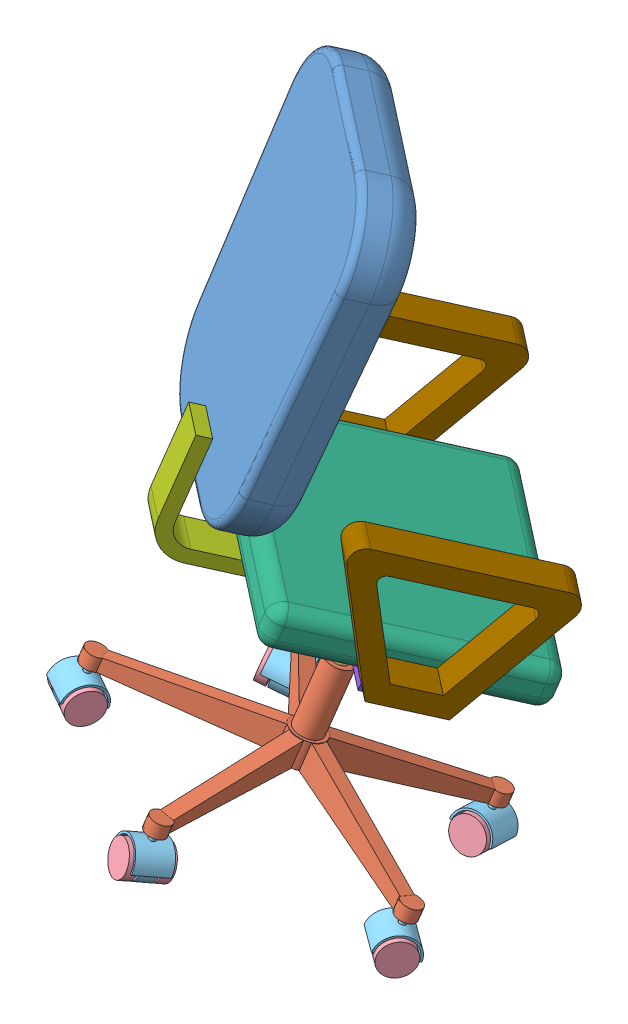
SolidWorks assembly Assem2, configuration Default. Lengths in mm.
Overall size (662.53 1073.07 669.63).
23 component instances, 9 part files, 42 mates.
Components (placement in the parent):
- back rest-1: back rest [Default] at (-3518.8122 357.0651 -759.5656) x (-0.791753 0.043601 -0.609283) z (-0.242596 -0.937857 0.248135) size (389.74 80 499.37)
- base legs-1: base legs [Default] at (-3351.6108 -73.638 -779.0281) x (0.131839 0.221531 0.9662) z (-0.961127 0.26711 0.069903) size (482.25 160 505.53)
- nuematic rod-1: nuematic rod [Default] at (-3337.055 -17.3665 -793.9162) x (-0.791753 0.043601 -0.609283) z (0.560602 -0.344271 -0.753129) size (24 200 24)
- wheel-1: wheel [Default] at (-3597.754 -47.6682 -679.7172) x (0.280239 0.901558 -0.329635) z (-0.375607 0.419001 0.826654) size (50 15 50)
- wheels-1: wheels [Default] at (-3584.5031 -49.286 -672.8764) x (-0.400951 0.329838 0.854661) z (-0.242596 -0.937857 0.248135) size (60 50 75)
- ceat-2: ceat [Default] at (-3273.8894 228.6402 -860.2391) x (-0.791753 0.043601 -0.609283) z (-0.560602 0.344271 0.753129) size (400 60 350)
- wheel-2: wheel [Default] at (-3139.6275 -175.4673 -714.8494) x (0.520852 0.521565 -0.675783) z (-0.265905 0.851384 0.45215) size (50 15 50)
- wheel-3: wheel [Default] at (-3327.5473 -79.4294 -535.5873) x (-0.50983 0.70779 -0.488985) z (-0.773121 -0.62626 -0.100413) size (50 15 50)
- wheel-4: wheel [Default] at (-3546.6433 -130.494 -942.7976) x (0.497624 0.789061 0.360211) z (0.221963 -0.517294 0.826522) size (50 15 50)
- wheel-5: wheel [Default] at (-3338.8664 -69.6238 -509.5925) x (0.849668 -0.250011 0.464284) z (-0.368384 -0.911407 0.183385) size (50 15 50)
- wheel-6: wheel [Default] at (-3571.2521 -50.9037 -666.0356) x (-0.466913 -0.119328 0.876215) z (0.040078 0.98698 0.155769) size (50 15 50)
- wheel-7: wheel [Default] at (-3254.2495 -217.0971 -984.2579) x (0.711 0.648676 -0.271476) z (-0.680602 0.731877 -0.03373) size (50 15 50)
- wheel-8: wheel [Default] at (-3115.2922 -177.1415 -697.3854) x (-0.290606 -0.902298 0.318444) z (-0.507484 0.427485 0.748142) size (50 15 50)
- wheel-9: wheel [Default] at (-3521.4879 -140.4343 -955.7744) x (-0.537997 -0.377647 -0.753619) z (-0.086352 -0.864635 0.494923) size (50 15 50)
- wheel-10: wheel [Default] at (-3248.9453 -210.8346 -955.4022) x (-0.804244 0.593998 0.018921) z (0.56739 0.776911 -0.272908) size (50 15 50)
- wheels-2: wheels [Default] at (-3127.4599 -176.3044 -706.1174) x (0.532108 -0.342504 -0.774307) z (-0.242596 -0.937857 0.248135) size (60 50 75)
- wheels-3: wheels [Default] at (-3251.5974 -213.9659 -969.83) x (0.95388 -0.277214 -0.115178) z (-0.242596 -0.937857 0.248135) size (60 50 75)
- wheels-4: wheels [Default] at (-3333.2069 -74.5266 -522.5899) x (0.89375 -0.116586 0.433149) z (-0.242596 -0.937857 0.248135) size (60 50 75)
- wheels-5: wheels [Default] at (-3534.0656 -135.4642 -949.286) x (0.487898 0.103127 0.866787) z (-0.242596 -0.937857 0.248135) size (60 50 75)
- ceat rest connector-1: ceat rest connector [Default] at (-3382.5087 277.3327 -661.4926) x (-0.560602 0.344271 0.753129) z (-0.242596 -0.937857 0.248135) size (157.54 60 170)
- ceat frame-1: ceat frame [Default] at (-3287.4946 172.7003 -843.1689) x (-0.791753 0.043601 -0.609283) z (-0.560602 0.344271 0.753129) size (430 10 200)
- hand rest-1: hand rest [Default] at (-2989.4453 279.844 -897.9504) x (-0.560602 0.344271 0.753129) z (0.242596 0.937857 -0.248135) size (275.28 50 200)
- hand rest-2: hand rest [Default] at (-3498.3858 415.3407 -883.4039) x (0.560602 -0.344271 -0.753129) z (0.242596 0.937857 -0.248135) size (275.28 50 200)
Mates (geometry in assembly coordinates):
- Coincident2: coincident aligned: circle of wheel-1; plane of wheels-1 through (-3606.5879 -46.5898 -684.2777) normal (-0.883394 0.107847 -0.456052)
- Concentric4: concentric aligned: cylinder of wheel-1 through (-3606.5879 -46.5898 -684.2777) axis (0.883394 -0.107847 0.456052) radius 5; cylinder of wheels-1 through (-3606.5879 -46.5898 -684.2777) axis (0.883394 -0.107847 0.456052) radius 5
- Coincident3: coincident anti-aligned: plane of wheels-1 through (-3562.4182 -51.9821 -661.4751) normal (0.883394 -0.107847 0.456052); plane of wheel-6 through (-3562.4182 -51.9821 -661.4751) normal (-0.883394 0.107847 -0.456052)
- Concentric5: concentric anti-aligned: cylinder of wheels-1 through (-3606.5879 -46.5898 -684.2777) axis (0.883394 -0.107847 0.456052) radius 5; cylinder of wheel-6 through (-3562.4182 -51.9821 -661.4751) axis (-0.883394 0.107847 -0.456052) radius 5
- Coincident4: coincident anti-aligned: circle of base legs-1; plane of wheels-1 through (-3572.3732 -2.3931 -685.2831) normal (0.242596 0.937857 -0.248135)
- Concentric6: concentric aligned: cylinder of base legs-1 through (-3572.3732 -2.3931 -685.2831) axis (-0.242596 -0.937857 0.248135) radius 5; cylinder of wheels-1 through (-3572.3732 -2.3931 -685.2831) axis (-0.242596 -0.937857 0.248135) radius 5
- Coincident5: coincident anti-aligned: plane of base legs-1 through (-3321.0771 -27.6337 -534.9967) normal (-0.242596 -0.937857 0.248135); plane of wheels-4 through (-3321.0771 -27.6337 -534.9967) normal (0.242596 0.937857 -0.248135)
- Concentric7: concentric aligned: cylinder of base legs-1 through (-3321.0771 -27.6337 -534.9967) axis (-0.242596 -0.937857 0.248135) radius 5; cylinder of wheels-4 through (-3321.0771 -27.6337 -534.9967) axis (-0.242596 -0.937857 0.248135) radius 5
- Coincident6: coincident aligned: plane of base legs-1 through (-3521.9358 -88.5713 -961.6927) normal (-0.242596 -0.937857 0.248135); circle of wheels-5
- Concentric8: concentric aligned: cylinder of base legs-1 through (-3521.9358 -88.5713 -961.6927) axis (-0.242596 -0.937857 0.248135) radius 5; cylinder of wheels-5 through (-3521.9358 -88.5713 -961.6927) axis (-0.242596 -0.937857 0.248135) radius 5
- Coincident8: coincident anti-aligned: plane of base legs-1 through (-3239.4676 -167.073 -982.2368) normal (-0.242596 -0.937857 0.248135); plane of wheels-3 through (-3239.4676 -167.073 -982.2368) normal (0.242596 0.937857 -0.248135)
- Concentric9: concentric aligned: cylinder of base legs-1 through (-3239.4676 -167.073 -982.2368) axis (-0.242596 -0.937857 0.248135) radius 5; cylinder of wheels-3 through (-3239.4676 -167.073 -982.2368) axis (-0.242596 -0.937857 0.248135) radius 5
- Coincident9: coincident anti-aligned: plane of base legs-1 through (-3115.3301 -129.4115 -718.5242) normal (-0.242596 -0.937857 0.248135); plane of wheels-2 through (-3115.3301 -129.4115 -718.5242) normal (0.242596 0.937857 -0.248135)
- Concentric10: concentric aligned: cylinder of base legs-1 through (-3115.3301 -129.4115 -718.5242) axis (-0.242596 -0.937857 0.248135) radius 5; cylinder of wheels-2 through (-3115.3301 -129.4115 -718.5242) axis (-0.242596 -0.937857 0.248135) radius 5
- Coincident10: coincident anti-aligned: plane of wheel-7 through (-3256.0176 -219.1846 -993.8764) normal (0.176807 0.208749 0.961854); plane of wheels-3 through (-3256.0176 -219.1846 -993.8764) normal (-0.176807 -0.208749 -0.961854)
- Concentric11: concentric anti-aligned: cylinder of wheel-7 through (-3256.0176 -219.1846 -993.8764) axis (0.176807 0.208749 0.961854) radius 5; cylinder of wheels-3 through (-3247.1772 -208.7471 -945.7837) axis (-0.176807 -0.208749 -0.961854) radius 5
- Coincident11: coincident anti-aligned: plane of wheel-9 through (-3513.1028 -143.7478 -960.1) normal (-0.838512 0.331344 0.432561); plane of wheels-5 through (-3513.1028 -143.7478 -960.1) normal (0.838512 -0.331344 -0.432561)
- Concentric12: concentric anti-aligned: cylinder of wheel-9 through (-3513.1028 -143.7478 -960.1) axis (-0.838512 0.331344 0.432561) radius 5; cylinder of wheels-5 through (-3555.0284 -127.1806 -938.472) axis (0.838512 -0.331344 -0.432561) radius 5
- Coincident12: coincident anti-aligned: plane of wheel-2 through (-3147.7393 -174.9092 -720.6707) normal (0.811177 -0.055809 0.582132); plane of wheels-2 through (-3147.7393 -174.9092 -720.6707) normal (-0.811177 0.055809 -0.582132)
- Concentric13: concentric anti-aligned: cylinder of wheel-2 through (-3147.7393 -174.9092 -720.6707) axis (0.811177 -0.055809 0.582132) radius 5; cylinder of wheels-2 through (-3107.1804 -177.6996 -691.5641) axis (-0.811177 0.055809 -0.582132) radius 5
- Coincident13: coincident anti-aligned: plane of wheel-3 through (-3323.7743 -82.6979 -544.2523) normal (-0.377303 0.326851 0.866493); plane of wheels-4 through (-3323.7743 -82.6979 -544.2523) normal (0.377303 -0.326851 -0.866493)
- Concentric14: concentric anti-aligned: cylinder of wheel-3 through (-3323.7743 -82.6979 -544.2523) axis (-0.377303 0.326851 0.866493) radius 5; cylinder of wheels-4 through (-3342.6394 -66.3553 -500.9276) axis (0.377303 -0.326851 -0.866493) radius 5
- Coincident14: coincident anti-aligned: plane of wheel-10 through (-3247.1772 -208.7471 -945.7837) normal (-0.176807 -0.208749 -0.961854); plane of wheels-3 through (-3247.1772 -208.7471 -945.7837) normal (0.176807 0.208749 0.961854)
- Concentric15: concentric aligned: cylinder of wheel-10 through (-3247.1772 -208.7471 -945.7837) axis (-0.176807 -0.208749 -0.961854) radius 5; cylinder of wheels-3 through (-3247.1772 -208.7471 -945.7837) axis (-0.176807 -0.208749 -0.961854) radius 5
- Coincident15: coincident anti-aligned: plane of wheel-8 through (-3107.1804 -177.6996 -691.5641) normal (-0.811177 0.055809 -0.582132); plane of wheels-2 through (-3107.1804 -177.6996 -691.5641) normal (0.811177 -0.055809 0.582132)
- Concentric16: concentric aligned: cylinder of wheel-8 through (-3107.1804 -177.6996 -691.5641) axis (-0.811177 0.055809 -0.582132) radius 5; cylinder of wheels-2 through (-3107.1804 -177.6996 -691.5641) axis (-0.811177 0.055809 -0.582132) radius 5
- Coincident16: coincident anti-aligned: plane of wheel-5 through (-3342.6394 -66.3553 -500.9276) normal (0.377303 -0.326851 -0.866493); plane of wheels-4 through (-3342.6394 -66.3553 -500.9276) normal (-0.377303 0.326851 0.866493)
- Concentric17: concentric aligned: cylinder of wheel-5 through (-3342.6394 -66.3553 -500.9276) axis (0.377303 -0.326851 -0.866493) radius 5; cylinder of wheels-4 through (-3342.6394 -66.3553 -500.9276) axis (0.377303 -0.326851 -0.866493) radius 5
- Coincident17: coincident anti-aligned: plane of wheel-4 through (-3555.0284 -127.1806 -938.472) normal (0.838512 -0.331344 -0.432561); plane of wheels-5 through (-3555.0284 -127.1806 -938.472) normal (-0.838512 0.331344 0.432561)
- Concentric18: concentric aligned: cylinder of wheel-4 through (-3555.0284 -127.1806 -938.472) axis (0.838512 -0.331344 -0.432561) radius 5; cylinder of wheels-5 through (-3555.0284 -127.1806 -938.472) axis (0.838512 -0.331344 -0.432561) radius 5
- Lock6: lock: unknown of nuematic rod-1; unknown of ceat frame-1
- Lock7: lock: unknown of ceat-2; unknown of ceat frame-1
- Lock9: lock: unknown of ceat-2; unknown of ceat rest connector-1
- Lock8: lock: unknown of back rest-1; unknown of ceat rest connector-1
- Coincident27: coincident anti-aligned: plane of ceat frame-1 through (-3287.4946 172.7003 -843.1689) normal (0.242596 0.937857 -0.248135); plane of hand rest-1 through (-3063.1633 144.6766 -729.7643) normal (-0.242596 -0.937857 0.248135)
- Coincident29: coincident anti-aligned: plane of ceat-2 through (-3228.1998 223.8961 -591.6968) normal (0.791753 -0.043601 0.609283); plane of hand rest-1 through (-2989.4453 279.844 -897.9504) normal (-0.791753 0.043601 -0.609283)
- Coincident30: coincident aligned: line of ceat frame-1 through (-3089.2377 146.1125 -749.8294) axis (-0.791753 0.043601 -0.609283); line of hand rest-1 through (-3063.1633 144.6766 -729.7643) axis (-0.791753 0.043601 -0.609283)
- Coincident31: coincident anti-aligned: plane of ceat-2 through (-3544.901 241.3365 -835.4101) normal (-0.791753 0.043601 -0.609283); plane of hand rest-2 through (-3498.3858 415.3407 -883.4039) normal (0.791753 -0.043601 0.609283)
- Coincident32: coincident anti-aligned: plane of ceat frame-1 through (-3287.4946 172.7003 -843.1689) normal (0.242596 0.937857 -0.248135); plane of hand rest-2 through (-3515.1 200.9042 -959.0931) normal (-0.242596 -0.937857 0.248135)
- Coincident33: coincident aligned: line of ceat frame-1 through (-3485.7516 199.2881 -936.5084) axis (0.791753 -0.043601 0.609283); line of hand rest-2 through (-3515.1 200.9042 -959.0931) axis (0.791753 -0.043601 0.609283)
- Concentric21: concentric anti-aligned: cylinder of base legs-1 through (-3337.055 -17.3665 -793.9162) axis (0.242596 0.937857 -0.248135) radius 12; cylinder of nuematic rod-1 through (-3288.5358 170.2049 -843.5432) axis (-0.242596 -0.937857 0.248135) radius 12
- Coincident35: coincident anti-aligned: plane of base legs-1 through (-3337.055 -17.3665 -793.9162) normal (0.242596 0.937857 -0.248135); plane of nuematic rod-1 through (-3337.055 -17.3665 -793.9162) normal (-0.242596 -0.937857 0.248135)
